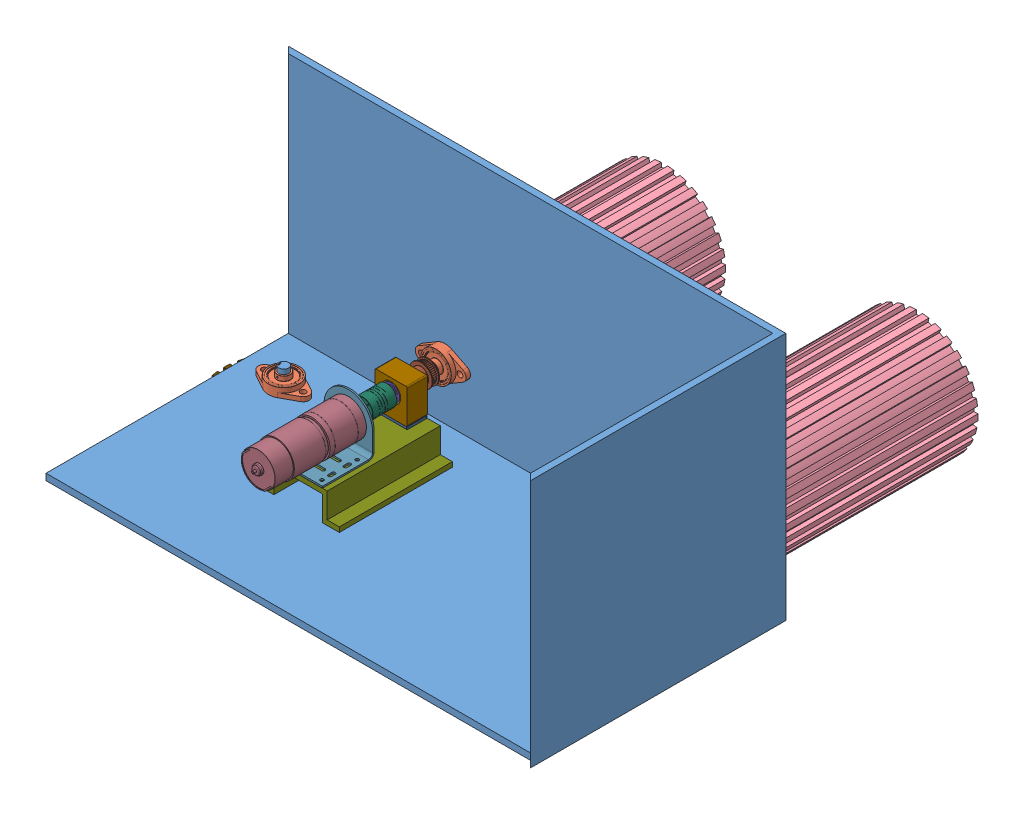
SolidWorks assembly moter in box assemly with 100mm supporting wheels - Copy (2), configuration Default. Lengths in mm.
Overall size (671.77 418 580.4).
82 component instances, 19 part files, 8 mates.
Components (placement in the parent):
- box-1: box [Default] at (214.7869 209.4239 556.9442) size (616 308 316)
- wheel without moter subassembley-1: wheel without moter subassembley [Default] at (363.3222 36.9 0) size (173.81 173.65 354)
  - KFL001 block flange ball bearing 12 diameter shaft-1: KFL001 block flange ball bearing 12 diameter shaft [Default] at (58.0648 247.4239 406.9442) x (-0.381567 0.924341 0) z (0.924341 0.381567 0) size (38 16 63)
  - wheel shaft-1: wheel shaft [Default] at (58.0648 247.4239 234.5442) x (0.174278 -0.984697 0) z (-0.984697 -0.174278 0) size (12 354 12)
  - wheel rubber-1: wheel rubber [Default] at (58.0648 247.4239 134.5442) x (-0.174278 0.984697 0) z (0.984697 0.174278 0) size (149.8 250 150)
  - wheel rim-1: wheel rim [Default] at (58.0648 247.4239 134.5442) x (-0.174278 0.984697 0) z (0.984697 0.174278 0) size (130 250 130)
  - Bearing House v1.step-1: Bearing House v1.step [Default] at (58.0648 227.9239 462.9398) x (-1 0 0) z (0 1 0) size (40 25 45.94)
    - SKF_61901-2Z.step-1: SKF_61901-2Z.step [Default] at (0 -8 19.5) x (0 -1 0) z (0 0 1) size (6 24 24)
      - SKF_61901-2Z_ball1.step-1: SKF_61901-2Z_ball1.step [Default] at (6 16.2812 -5.2901) x (-1 0 0) z (0 0 1) size (3.18 3.17 3.17)
      - SKF_61901-2Z_ball1.step-2: SKF_61901-2Z_ball1.step [Default] at (6 11.7812 -8.5595) x (-1 0 0) z (0 0 1) size (3.18 3.17 3.17)
      - SKF_61901-2Z_ball1.step-3: SKF_61901-2Z_ball1.step [Default] at (6 6.2188 -8.5595) x (-1 0 0) z (0 0 1) size (3.18 3.17 3.17)
      - SKF_61901-2Z_ball1.step-4: SKF_61901-2Z_ball1.step [Default] at (6 1.7188 -5.2901) x (-1 0 0) z (0 0 1) size (3.18 3.17 3.17)
      - SKF_61901-2Z_ball1.step-5: SKF_61901-2Z_ball1.step [Default] at (6 0 0) x (-1 0 0) z (0 0 1) size (3.18 3.17 3.17)
      - SKF_61901-2Z_ball1.step-6: SKF_61901-2Z_ball1.step [Default] at (6 1.7188 5.2901) x (-1 0 0) z (0 0 1) size (3.18 3.17 3.17)
      - SKF_61901-2Z_ball1.step-7: SKF_61901-2Z_ball1.step [Default] at (6 6.2188 8.5595) x (-1 0 0) z (0 0 1) size (3.18 3.17 3.17)
      - SKF_61901-2Z_ball1.step-8: SKF_61901-2Z_ball1.step [Default] at (6 11.7812 8.5595) x (-1 0 0) z (0 0 1) size (3.18 3.17 3.17)
      - SKF_61901-2Z_ball1.step-9: SKF_61901-2Z_ball1.step [Default] at (6 16.2812 5.2901) x (-1 0 0) z (0 0 1) size (3.18 3.17 3.17)
      - SKF_61901-2Z_ball1.step-10: SKF_61901-2Z_ball1.step [Default] at (6 18 0) x (-1 0 0) z (0 0 1) size (3.18 3.17 3.17)
      - SKF_61901-2Z_or.step-1: SKF_61901-2Z_or.step [Default] x (1 0 0) z (0 0 -1) size (6 24 24)
      - SKF_61901-2Z_ir.step-1: SKF_61901-2Z_ir.step [Default] x (1 0 0) z (0 0 -1) size (6 21.4 21.4)
    - SKF_61901-2Z.step-2: SKF_61901-2Z.step [Default] at (0 5 19.5) x (0 1 0) z (0 0 1) size (6 24 24)
      - SKF_61901-2Z_ball1.step-1: SKF_61901-2Z_ball1.step [Default] at (6 16.2812 -5.2901) x (-1 0 0) z (0 0 1) size (3.18 3.17 3.17)
      - SKF_61901-2Z_ball1.step-2: SKF_61901-2Z_ball1.step [Default] at (6 11.7812 -8.5595) x (-1 0 0) z (0 0 1) size (3.18 3.17 3.17)
      - SKF_61901-2Z_ball1.step-3: SKF_61901-2Z_ball1.step [Default] at (6 6.2188 -8.5595) x (-1 0 0) z (0 0 1) size (3.18 3.17 3.17)
      - SKF_61901-2Z_ball1.step-4: SKF_61901-2Z_ball1.step [Default] at (6 1.7188 -5.2901) x (-1 0 0) z (0 0 1) size (3.18 3.17 3.17)
      - SKF_61901-2Z_ball1.step-5: SKF_61901-2Z_ball1.step [Default] at (6 0 0) x (-1 0 0) z (0 0 1) size (3.18 3.17 3.17)
      - SKF_61901-2Z_ball1.step-6: SKF_61901-2Z_ball1.step [Default] at (6 1.7188 5.2901) x (-1 0 0) z (0 0 1) size (3.18 3.17 3.17)
      - SKF_61901-2Z_ball1.step-7: SKF_61901-2Z_ball1.step [Default] at (6 6.2188 8.5595) x (-1 0 0) z (0 0 1) size (3.18 3.17 3.17)
      - SKF_61901-2Z_ball1.step-8: SKF_61901-2Z_ball1.step [Default] at (6 11.7812 8.5595) x (-1 0 0) z (0 0 1) size (3.18 3.17 3.17)
      - SKF_61901-2Z_ball1.step-9: SKF_61901-2Z_ball1.step [Default] at (6 16.2812 5.2901) x (-1 0 0) z (0 0 1) size (3.18 3.17 3.17)
      - SKF_61901-2Z_ball1.step-10: SKF_61901-2Z_ball1.step [Default] at (6 18 0) x (-1 0 0) z (0 0 1) size (3.18 3.17 3.17)
      - SKF_61901-2Z_or.step-1: SKF_61901-2Z_or.step [Default] x (1 0 0) z (0 0 -1) size (6 24 24)
      - SKF_61901-2Z_ir.step-1: SKF_61901-2Z_ir.step [Default] x (1 0 0) z (0 0 -1) size (6 21.4 21.4)
    - Universal Bearing Housing.step-1: Universal Bearing Housing.step [Default] at (0 11.0044 14.0358) x (1 0 0) z (0 -1 0) size (40 43 25)
    - Universal Bearing Housing Spacer.step-1: Universal Bearing Housing Spacer.step [Default] at (0 -1.5 -7.4) x (1 0 0) z (0 1 0) size (40 3 25)
  - GT2 40T id 12mm bw 7mm-1: GT2 40T id 12mm bw 7mm [Výchozí] at (58.0648 247.4239 435.4442) x (0.924379 0.381477 0) z (0.381477 -0.924379 0) size (28.2 17 28.2)
  - height extender 25mm-1: height extender 25mm [Default] at (7.0648 186.5239 448.9398) size (102 37 25)
- Wheel with moter assembly-1: Wheel with moter assembly [Default] at (38.7886 37 0) size (163.26 163.44 510.81)
  - Motor DC PG45-1: Motor DC PG45 [Default] at (70.1664 247.4239 638.3442) x (0.707107 0.707107 0) z (-0.707107 0.707107 0) size (45 146.01 45)
  - Mounting Bracket Motor DC PG45 Orange-1: Mounting Bracket Motor DC PG45 Orange [Default] at (91.7552 243.9192 526.8442) x (-1 0 0) z (0 0 -1) size (60 60 63.93)
  - KFL001 block flange ball bearing 12 diameter shaft-1: KFL001 block flange ball bearing 12 diameter shaft [Default] at (70.1664 247.4239 406.9442) x (-0.034258 0.999413 0) z (0.999413 0.034258 0) size (38 16 63)
  - wheel shaft-1: wheel shaft [Default] at (70.1664 247.4239 234.5442) x (0.995554 -0.094191 0) z (-0.094191 -0.995554 0) size (12 354 12)
  - Shaft_Coupler_6.35x12mm-1: Shaft_Coupler_6.35x12mm [По умолчанию] at (70.1664 247.4239 508.9442) x (0.647293 0.762241 0) z (-0.762241 0.647293 0) size (25.41 30 25.41)
  - wheel rubber-1: wheel rubber [Default] at (70.1664 247.4239 134.5442) x (-0.995554 0.094191 0) z (0.094191 0.995554 0) size (149.8 250 150)
  - wheel rim-1: wheel rim [Default] at (70.1664 247.4239 134.5442) x (-0.995554 0.094191 0) z (0.094191 0.995554 0) size (130 250 130)
  - Bearing House v1.step-1: Bearing House v1.step [Default] at (70.1664 227.9239 462.9398) x (-1 0 0) z (0 1 0) size (40 25 45.94)
    - SKF_61901-2Z.step-1: SKF_61901-2Z.step [Default] at (0 -8 19.5) x (0 -1 0) z (0 0 1) size (6 24 24)
      - SKF_61901-2Z_ball1.step-1: SKF_61901-2Z_ball1.step [Default] at (6 16.2812 -5.2901) x (-1 0 0) z (0 0 1) size (3.18 3.17 3.17)
      - SKF_61901-2Z_ball1.step-2: SKF_61901-2Z_ball1.step [Default] at (6 11.7812 -8.5595) x (-1 0 0) z (0 0 1) size (3.18 3.17 3.17)
      - SKF_61901-2Z_ball1.step-3: SKF_61901-2Z_ball1.step [Default] at (6 6.2188 -8.5595) x (-1 0 0) z (0 0 1) size (3.18 3.17 3.17)
      - SKF_61901-2Z_ball1.step-4: SKF_61901-2Z_ball1.step [Default] at (6 1.7188 -5.2901) x (-1 0 0) z (0 0 1) size (3.18 3.17 3.17)
      - SKF_61901-2Z_ball1.step-5: SKF_61901-2Z_ball1.step [Default] at (6 0 0) x (-1 0 0) z (0 0 1) size (3.18 3.17 3.17)
      - SKF_61901-2Z_ball1.step-6: SKF_61901-2Z_ball1.step [Default] at (6 1.7188 5.2901) x (-1 0 0) z (0 0 1) size (3.18 3.17 3.17)
      - SKF_61901-2Z_ball1.step-7: SKF_61901-2Z_ball1.step [Default] at (6 6.2188 8.5595) x (-1 0 0) z (0 0 1) size (3.18 3.17 3.17)
      - SKF_61901-2Z_ball1.step-8: SKF_61901-2Z_ball1.step [Default] at (6 11.7812 8.5595) x (-1 0 0) z (0 0 1) size (3.18 3.17 3.17)
      - SKF_61901-2Z_ball1.step-9: SKF_61901-2Z_ball1.step [Default] at (6 16.2812 5.2901) x (-1 0 0) z (0 0 1) size (3.18 3.17 3.17)
      - SKF_61901-2Z_ball1.step-10: SKF_61901-2Z_ball1.step [Default] at (6 18 0) x (-1 0 0) z (0 0 1) size (3.18 3.17 3.17)
      - SKF_61901-2Z_or.step-1: SKF_61901-2Z_or.step [Default] x (1 0 0) z (0 0 -1) size (6 24 24)
      - SKF_61901-2Z_ir.step-1: SKF_61901-2Z_ir.step [Default] x (1 0 0) z (0 0 -1) size (6 21.4 21.4)
    - SKF_61901-2Z.step-2: SKF_61901-2Z.step [Default] at (0 5 19.5) x (0 1 0) z (0 0 1) size (6 24 24)
      - SKF_61901-2Z_ball1.step-1: SKF_61901-2Z_ball1.step [Default] at (6 16.2812 -5.2901) x (-1 0 0) z (0 0 1) size (3.18 3.17 3.17)
      - SKF_61901-2Z_ball1.step-2: SKF_61901-2Z_ball1.step [Default] at (6 11.7812 -8.5595) x (-1 0 0) z (0 0 1) size (3.18 3.17 3.17)
      - SKF_61901-2Z_ball1.step-3: SKF_61901-2Z_ball1.step [Default] at (6 6.2188 -8.5595) x (-1 0 0) z (0 0 1) size (3.18 3.17 3.17)
      - SKF_61901-2Z_ball1.step-4: SKF_61901-2Z_ball1.step [Default] at (6 1.7188 -5.2901) x (-1 0 0) z (0 0 1) size (3.18 3.17 3.17)
      - SKF_61901-2Z_ball1.step-5: SKF_61901-2Z_ball1.step [Default] at (6 0 0) x (-1 0 0) z (0 0 1) size (3.18 3.17 3.17)
      - SKF_61901-2Z_ball1.step-6: SKF_61901-2Z_ball1.step [Default] at (6 1.7188 5.2901) x (-1 0 0) z (0 0 1) size (3.18 3.17 3.17)
      - SKF_61901-2Z_ball1.step-7: SKF_61901-2Z_ball1.step [Default] at (6 6.2188 8.5595) x (-1 0 0) z (0 0 1) size (3.18 3.17 3.17)
      - SKF_61901-2Z_ball1.step-8: SKF_61901-2Z_ball1.step [Default] at (6 11.7812 8.5595) x (-1 0 0) z (0 0 1) size (3.18 3.17 3.17)
      - SKF_61901-2Z_ball1.step-9: SKF_61901-2Z_ball1.step [Default] at (6 16.2812 5.2901) x (-1 0 0) z (0 0 1) size (3.18 3.17 3.17)
      - SKF_61901-2Z_ball1.step-10: SKF_61901-2Z_ball1.step [Default] at (6 18 0) x (-1 0 0) z (0 0 1) size (3.18 3.17 3.17)
      - SKF_61901-2Z_or.step-1: SKF_61901-2Z_or.step [Default] x (1 0 0) z (0 0 -1) size (6 24 24)
      - SKF_61901-2Z_ir.step-1: SKF_61901-2Z_ir.step [Default] x (1 0 0) z (0 0 -1) size (6 21.4 21.4)
    - Universal Bearing Housing.step-1: Universal Bearing Housing.step [Default] at (0 11.0044 14.0358) x (1 0 0) z (0 -1 0) size (40 43 25)
    - Universal Bearing Housing Spacer.step-1: Universal Bearing Housing Spacer.step [Default] at (0 -1.5 -7.4) x (1 0 0) z (0 1 0) size (40 3 25)
  - GT2 40T id 12mm bw 7mm-1: GT2 40T id 12mm bw 7mm [Výchozí] at (70.1664 247.4239 435.4442) x (0.924379 0.381477 0) z (0.381477 -0.924379 0) size (28.2 17 28.2)
  - height extender 140mm-1: height extender 140mm [Default] at (19.1664 186.4239 448.9442) size (102 37 140)
- support wheel with block flange 100mm assembly-1: support wheel with block flange 100mm assembly [Default] at (-341.3848 337.3003 401.9413) x (0.243495 0 0.969902) z (0.969902 0 -0.243495) size (211.82 140 211.83)
  - side wheel (rubber+rim)-1: side wheel (rubber+rim) [Default] at (69.3134 97.8604 176.3592) size (211.82 100 211.83)
    - side wheel rim-1: side wheel rim [Default] at (68.1365 40.0161 108.3416) size (130 100 130)
    - side wheel rubber-1: side wheel rubber [Default] at (68.1365 40.0161 108.3416) x (0.734903 0 0.678172) z (-0.678172 0 0.734903) size (149.8 100 150)
  - support wheel shaft 100mm-1: support wheel shaft 100mm [Default] at (137.4499 201.8764 284.7008) x (1 0 0) z (0 0 -1) size (12 140 12)
  - KFL001 block flange ball bearing 12 diameter shaft-1: KFL001 block flange ball bearing 12 diameter shaft [Default] at (137.4499 119.8764 284.7008) x (-0.969898 0 0.243511) z (0.243511 0 0.969898) size (38 16 63)
Mates (geometry in assembly coordinates):
- Parallel6: parallel anti-aligned: line of box-1 through (-85.2131 217.4239 406.9442) axis (0 0 1); line of wheel without moter subassembley-1/Bearing House v1.step-1/Universal Bearing Housing Spacer.step-1 through (401.3869 254.4239 472.9398) axis (0 0 -1)
- Parallel7: parallel anti-aligned: line of box-1 through (-85.2131 217.4239 706.9442) axis (1 0 0); line of wheel without moter subassembley-1/Bearing House v1.step-1/Universal Bearing Housing Spacer.step-1 through (440.3869 254.4239 473.9398) axis (-1 0 0)
- Coincident18: coincident anti-aligned: plane of box-1 through (214.7869 517.4239 406.9442) normal (0 0 1); plane of wheel without moter subassembley-1/KFL001 block flange ball bearing 12 diameter shaft-1 through (421.3869 284.3239 406.9442) normal (0 0 -1)
- Coincident22: coincident anti-aligned: plane of box-1 through (214.7869 217.4239 556.9442) normal (0 1 0); plane of wheel without moter subassembley-1/height extender 25mm-1 through (391.3869 217.4239 473.9398) normal (0 -1 0)
- Coincident23: coincident anti-aligned: plane of box-1 through (214.7869 217.4239 556.9442) normal (0 1 0); plane of Wheel with moter assembly-1/height extender 140mm-1 through (78.955 217.4239 588.9442) normal (0 -1 0)
- Coincident24: coincident anti-aligned: plane of box-1 through (214.7869 517.4239 406.9442) normal (0 0 1); plane of Wheel with moter assembly-1/KFL001 block flange ball bearing 12 diameter shaft-1 through (108.955 284.4239 406.9442) normal (0 0 -1)
- Coincident25: coincident anti-aligned: plane of box-1 through (214.7869 217.4239 556.9442) normal (0 1 0); plane of support wheel with block flange 100mm assembly-1/KFL001 block flange ball bearing 12 diameter shaft-1 through (-31.7846 217.4239 465.9312) normal (0 -1 0)
- Angle3: planar angle = 0.499688 rad aligned: line of support wheel with block flange 100mm assembly-1/KFL001 block flange ball bearing 12 diameter shaft-1 through (-22.6807 217.4239 482.6081) axis (0.877732 0 -0.479152); line of box-1 through (-85.2131 217.4239 406.9442) axis (1 0 0)
